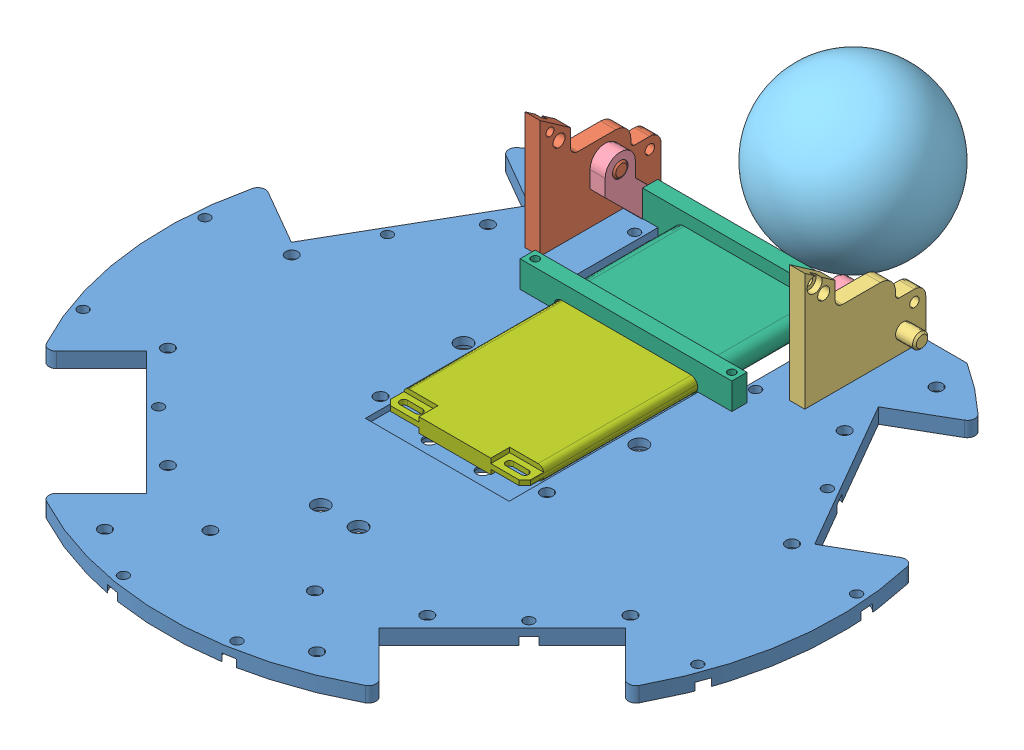
SolidWorks assembly chip_kicker_test1, configuration Default. Lengths in mm.
Overall size (178 52.67 207.59).
7 component instances, 7 part files, 12 mates.
Components (placement in the parent):
- base-1: base [Default] at (76.3084 55.3199 148.5901) size (178 4 164)
- 1 side support left-1: 1 side support left [Default] at (43.3084 59.3199 73.5901) x (0 0 1) z (-1 0 0) size (32 31.1 14)
- 1 side support right-1: 1 side support right [Default] at (113.3084 59.3199 73.5901) x (0 0 1) z (-1 0 0) size (32 31.1 14)
- 1 chip kicker-1: 1 chip kicker [Default] at (47.4094 51.939 67.4716) x (0 0.005525 -0.999985) z (0 0.999985 0.005525) size (24.09 65 25.5)
- golf_ball-1: golf_ball [Default] at (74.9828 60.9116 52.9797) x (0.998172 -0.060152 -0.005901) z (-0.005901 -0.194172 0.98095) size (42.7 42.7 42.7)
- 1 chip solenoid shell-1: 1 chip solenoid shell [Default] at (76.2084 60.3199 111.7901) x (1 0 0) z (0 1 0) size (56 36.4 12)
- 1 chip plunger-1: 1 chip plunger [Default] at (76.3023 60.2199 135.1215) x (0 0 1) z (-1 0 0) size (52 3.8 37)
Mates (geometry in assembly coordinates):
- Concentric3: concentric aligned: circle of base-1; circle of 1 side support left-1
- Concentric4: concentric aligned: circle of base-1; circle of 1 side support left-1
- Coincident3: coincident anti-aligned: plane of base-1 through (135.9442 59.3199 85.2452) normal (0 1 0); plane of 1 side support left-1 through (39.3084 59.3199 105.5901) normal (0 -1 0)
- Concentric5: concentric aligned: circle of base-1; circle of 1 side support right-1
- Concentric6: concentric aligned: circle of base-1; circle of 1 side support right-1
- Coincident4: coincident anti-aligned: plane of base-1 through (135.9442 59.3199 85.2452) normal (0 1 0); plane of 1 side support right-1 through (113.3084 59.3199 73.5901) normal (0 -1 0)
- Concentric7: concentric anti-aligned: circle of 1 side support left-1; circle of 1 chip kicker-1
- Concentric8: concentric aligned: cylinder of 1 side support right-1 through (104.3084 73.3199 89.0901) axis (1 0 0) radius 2; circle of 1 chip kicker-1
- Coincident5: coincident anti-aligned: line of base-1 through (52.3084 59.3199 115.7901) axis (1 0 0); line of 1 chip solenoid shell-1 through (52.3084 59.3199 115.7901) axis (-1 0 0)
- Coincident6: coincident aligned: line of base-1 through (52.3084 55.3199 115.7901) axis (0 1 0); line of 1 chip solenoid shell-1 through (52.3084 54.3199 115.7901) axis (0 1 0)
- Coincident7: coincident anti-aligned: plane of 1 chip solenoid shell-1 through (59.2084 58.3199 79.3901) normal (0 1 0); plane of 1 chip plunger-1 through (76.3023 58.3199 135.1215) normal (0 -1 0)
- Parallel1: parallel aligned: line of 1 chip solenoid shell-1 through (93.2084 62.3199 115.7901) axis (-1 0 0); line of 1 chip plunger-1 through (93.3023 62.1199 110.6215) axis (-1 0 0)
